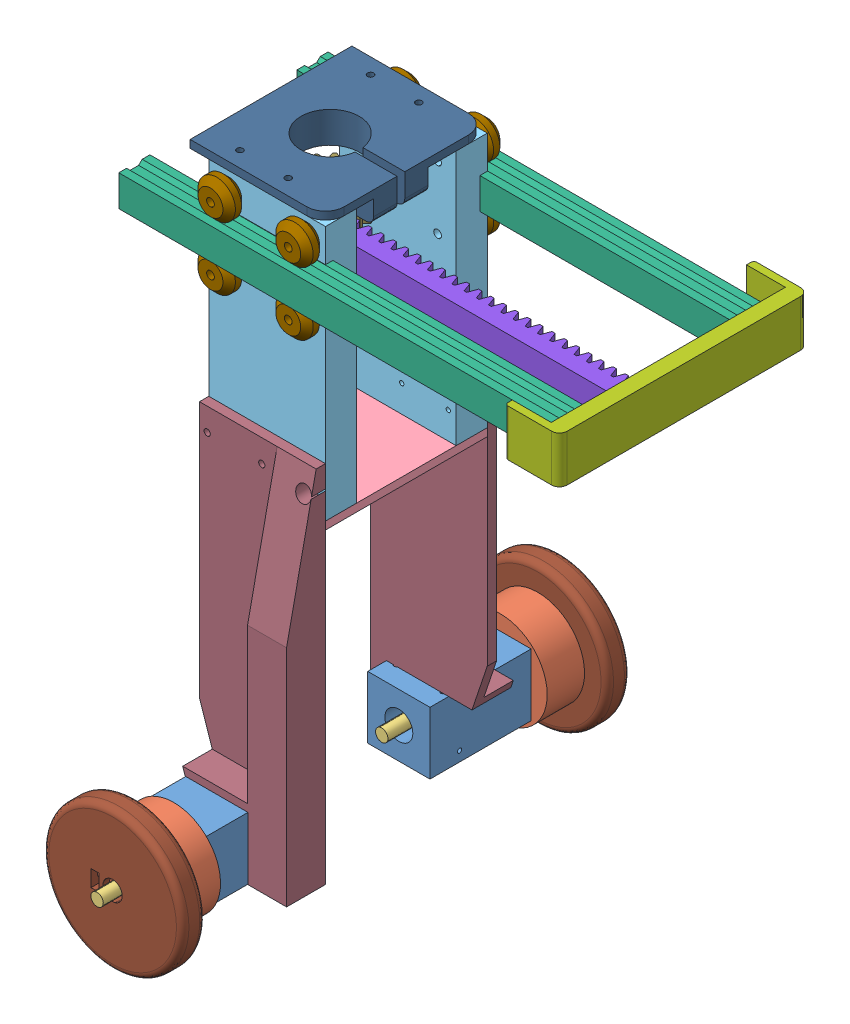
SolidWorks assembly assembly, configuration Default. Lengths in mm.
Overall size (288 396.18 308).
28 component instances, 14 part files, 40 mates.
Components (placement in the parent):
- backSlider.stp-1-solid27-1: backSlider.stp-1-solid27 [Default] at (-286.5622 -346.0796 -57.1007) x (-1 0 0) z (0 0 1) size (40 40 65)
- Part87-1: Part87 [Default] at (-286.5622 -346.0796 7.8993) x (-0.760275 0.649602 0) z (0 0 1) size (60 60 24)
- Part89-1: Part89 [Default] at (-286.5622 -346.0796 -68.1007) x (-0.760275 0.649602 0) z (0 0 1) size (12.4 12.4 125)
- Part90-1: Part90 [Default] at (-279.2282 -164 -97.1007) x (1 0 0) z (0 -1 0) size (75 104 5)
- Part91-1: Part91 [Default] at (-279.2282 -82 -65.1007) size (75 164 20)
- Part93-1: Part93 [Default] at (-359.3481 -31.25 -39.8507) x (0 -1 0) z (1 0 0) size (20 20 278)
- Part94-1: Part94 [Default] at (-88.8481 -21.25 -105.1005) x (-1 0 0) z (0 -1 0) size (35 160 30)
- Part95-1: Part95 [Default] at (-201.3481 -36.25 -72.9132) x (-1 0 0) z (0 -1 0) size (240 15.62 54)
- Part96-1: Part96 [Default] at (-303.6445 -11.5 -45.1007) x (0.999988 -0.004867 0) z (0 0 1) size (24 24 12)
- Part97-1: Part97 [Default] at (-285.2282 5 -97.1007) x (1 0 0) z (0 -1 0) size (87 104 20)
- wheel front without gear-2: wheel front without gear [Default] at (-813.0302 196.9967 26.563)
- wheel with grat-1: wheel with grat [Default] at (-286.5622 -346.0796 39.3993) x (-0.999998 -0.002215 0) z (0 0 1) size (90 90 15)
- Part96-2: Part96 [Default] at (-253.6445 -11.5 -33.1007) x (-0.928778 -0.370636 0) z (0 0 -1) size (24 24 12)
- Part96-3: Part96 [Default] at (-253.6445 -52 -45.1007) x (0.988499 0.151229 0) z (0 0 1) size (24 24 12)
- Part96-4: Part96 [Default] at (-303.6445 -52 -45.1007) x (0.982944 0.183903 0) z (0 0 1) size (24 24 12)
- Part98-1: Part98 [Default] at (-287.2282 -40.0491 -93.6007) x (1 0 0) z (0 1 0) size (40 39.32 20)
- Part99-1: Part99 [Default] at (-279.2282 -249.1667 -45.1007) x (-1 0 0) z (0 0 1) size (75 234.33 25)
- Part91-3: Part91 [Default] at (-279.2282 -82 -149.1007) size (75 164 20)
- Part96-9: Part96 [Default] at (-253.6445 -11.5 -149.1007) x (-0.928778 -0.370636 0) z (0 0 -1) size (24 24 12)
- Part96-10: Part96 [Default] at (-303.6445 -11.5 -161.1007) x (0.999988 -0.004867 0) z (0 0 1) size (24 24 12)
- Part96-11: Part96 [Default] at (-303.6445 -52 -161.1007) x (0.982944 0.183903 0) z (0 0 1) size (24 24 12)
- Part93-3: Part93 [Default] at (-81.3481 -31.25 -154.3507) x (0 -1 0) z (-1 0 0) size (20 20 278)
- Part99-4: Part99 [Default] at (-279.2282 -249.1667 -149.1007) x (1 0 0) z (0 0 -1) size (75 234.33 25)
- backSlider.stp-1-solid27-4: backSlider.stp-1-solid27 [Default] at (-286.5622 -346.0796 -137.1007) x (-1 0 0) z (0 0 -1) size (40 40 65)
- Part87-4: Part87 [Default] at (-286.5622 -346.0796 -226.1007) x (-0.760275 0.649602 0) z (0 0 1) size (60 60 24)
- wheel with grat-4: wheel with grat [Default] at (-286.5622 -346.0796 -233.6007) x (-0.999998 -0.002215 0) z (0 0 -1) size (90 90 15)
- Part89-4: Part89 [Default] at (-286.5622 -346.0796 -251.1007) x (-0.760275 0.649602 0) z (0 0 1) size (12.4 12.4 125)
- Part96-12: Part96 [Default] at (-253.6445 -52 -161.1007) x (0.988499 0.151229 0) z (0 0 1) size (24 24 12)
Mates (geometry in assembly coordinates):
- Coincident1: coincident anti-aligned: plane of Part97-1 through (-285.2282 0 -97.1007) normal (0 -1 0)
- Coincident2: coincident aligned: plane of Part91-1 through (-279.2282 -82 -45.1007) normal (0 0 1); plane of Part97-1 through (-285.2282 0 -45.1007) normal (0 0 1)
- Coincident3: coincident anti-aligned: plane of Part91-1 through (-241.7282 0 -45.1007) normal (0 1 0); plane of Part97-1 through (-285.2282 0 -97.1007) normal (0 -1 0)
- Coincident4: coincident aligned: plane of Part91-1 through (-241.7282 -164 -45.1007) normal (1 0 0); plane of Part97-1 through (-241.7282 0 -97.1007) normal (1 0 0)
- Concentric1: concentric aligned: cylinder of Part91-1 through (-303.6445 -11.5 -45.1007) axis (0 0 -1) radius 2.5; cylinder of Part96-1 through (-303.6445 -11.5 -33.1007) axis (0 0 -1) radius 2.5
- Coincident5: coincident anti-aligned: plane of Part91-1 through (-279.2282 -82 -45.1007) normal (0 0 1); plane of Part96-1 through (-303.6445 -11.5 -45.1007) normal (0 0 -1)
- Concentric2: concentric aligned: cylinder of Part91-1 through (-253.6445 -11.5 -45.1007) axis (0 0 -1) radius 2.5; circle of Part96-2
- Concentric3: concentric aligned: cylinder of Part91-1 through (-253.6445 -52 -45.1007) axis (0 0 -1) radius 2.5; cylinder of Part96-3 through (-253.6445 -52 -33.1007) axis (0 0 -1) radius 2.5
- Concentric4: concentric aligned: cylinder of Part91-1 through (-303.6445 -52 -45.1007) axis (0 0 -1) radius 2.5; cylinder of Part96-4 through (-303.6445 -52 -33.1007) axis (0 0 -1) radius 2.5
- Coincident7: coincident anti-aligned: plane of Part91-1 through (-279.2282 -82 -45.1007) normal (0 0 1); plane of Part96-2 through (-253.6445 -11.5 -45.1007) normal (0 0 -1)
- Coincident8: coincident anti-aligned: plane of Part91-1 through (-279.2282 -82 -45.1007) normal (0 0 1); plane of Part96-4 through (-303.6445 -52 -45.1007) normal (0 0 -1)
- Coincident9: coincident anti-aligned: plane of Part91-1 through (-279.2282 -82 -45.1007) normal (0 0 1); plane of Part96-3 through (-253.6445 -52 -45.1007) normal (0 0 -1)
- Concentric5: concentric anti-aligned: cylinder of Part97-1 through (-287.2282 -15 -93.6007) axis (0 1 0) radius 18.75; cylinder of Part98-1 through (-287.2282 -20.0491 -93.6007) axis (0 -1 0) radius 1.2268
- Parallel2: parallel anti-aligned: plane of Part93-1 through (-81.3481 -39 -37.1007) normal (0 -1 0); plane of Part97-1 through (-285.2282 5 -97.1007) normal (0 1 0)
- Parallel3: parallel aligned: plane of Part91-1 through (-241.7282 -164 -45.1007) normal (1 0 0); plane of Part93-1 through (-81.3481 -31.25 -39.8507) normal (1 0 0)
- Tangent1: tangent anti-aligned: plane of Part93-1 through (-81.3481 -23.5 -42.6007) normal (0 1 0); cylinder of Part96-2 through (-253.6445 -11.5 -45.1007) axis (0 0 1) radius 12
- Tangent2: tangent anti-aligned: plane of Part93-1 through (-81.3481 -23.5 -37.1007) normal (0 0.707108 -0.707106); cone of Part96-2 through (-253.6445 -11.5 -37.1007) axis (0 0 1)
- Coincident12: coincident anti-aligned: plane of Part93-1 through (-81.3481 -21.25 -29.8507) normal (0 0 1); plane of Part94-1 through (-106.3481 -51.25 -29.8507) normal (0 0 -1)
- Coincident13: coincident anti-aligned: plane of Part93-1 through (-81.3481 -31.25 -39.8507) normal (1 0 0); plane of Part94-1 through (-81.3481 -51.25 -29.8507) normal (-1 0 0)
- Coincident14: coincident aligned: plane of Part93-1 through (-81.3481 -21.25 -34.8507) normal (0 1 0); plane of Part94-1 through (-76.3481 -21.25 -180.1004) normal (0 1 0)
- Coincident15: coincident anti-aligned: plane of Part94-1 through (-81.3481 -51.25 -29.8507) normal (-1 0 0); plane of Part95-1 through (-81.3481 -51.25 -72.9132) normal (1 0 0)
- Coincident16: coincident aligned: plane of Part94-1 through (-76.3481 -21.25 -180.1004) normal (0 1 0); plane of Part95-1 through (-201.3481 -21.25 -72.9132) normal (0 1 0)
- Coincident17: coincident aligned: plane of Part94-1 through (-76.3481 -21.25 -180.1004) normal (0 1 0); plane of Part95-1 through (-201.3481 -21.25 -72.9132) normal (0 1 0)
- Coincident19: coincident anti-aligned: plane of Part91-1 through (-279.2282 -82 -45.1007) normal (0 0 1); plane of Part99-1 through (-279.2282 -249.1667 -45.1007) normal (0 0 -1)
- Coincident21: coincident aligned: plane of Part91-1 through (-241.7282 -164 -45.1007) normal (1 0 0); plane of Part99-1 through (-241.7282 -249.1667 -39.1007) normal (1 0 0)
- Concentric8: concentric aligned: cylinder of Part91-1 through (-311.7606 -146.6627 -45.1007) axis (0 0 -1) radius 1.4; cylinder of Part99-1 through (-311.7606 -146.6627 -39.1007) axis (0 0 -1) radius 2
- Concentric9: concentric aligned: cylinder of backSlider.stp-1-solid27-1 through (-286.5622 -346.0796 7.8993) axis (0 0 -1) radius 9; cylinder of Part89-1 through (-286.5622 -346.0796 56.8993) axis (0 0 -1) radius 4
- Concentric10: concentric anti-aligned: cylinder of Part89-1 through (-286.5622 -346.0796 56.8993) axis (0 0 -1) radius 4; circle of wheel with grat-1
- Concentric11: concentric aligned: cylinder of backSlider.stp-1-solid27-1 through (-286.5622 -346.0796 7.8993) axis (0 0 -1) radius 9; cylinder of Part87-1 through (-286.5622 -346.0796 31.8993) axis (0 0 -1) radius 12.5
- Coincident22: coincident anti-aligned: plane of Part87-1 through (-286.1973 -346.3915 31.8993) normal (0 0 1); plane of wheel with grat-1 through (-286.5622 -346.0796 31.8993) normal (0 0 -1)
- Coincident23: coincident anti-aligned: plane of backSlider.stp-1-solid27-1 through (-286.5622 -346.0796 7.8993) normal (0 0 1); plane of Part87-1 through (-286.1973 -346.3915 7.8993) normal (0 0 -1)
- Distance1: distance = 10 mm aligned: plane of wheel with grat-1 through (-286.5622 -346.0796 46.8993) normal (0 0 1); plane of Part89-1 through (-286.5622 -346.0796 56.8993) normal (0 0 1)
- Coincident27: coincident anti-aligned: plane of backSlider.stp-1-solid27-1 through (-266.5622 -326.0796 7.8993) normal (1 0 0); plane of Part99-1 through (-266.5622 -249.1667 -39.1007) normal (-1 0 0)
- Coincident28: coincident anti-aligned: plane of backSlider.stp-1-solid27-1 through (-266.5622 -326.0796 7.8993) normal (0 1 0); plane of Part99-1 through (-279.2282 -326.0796 -39.1007) normal (0 -1 0)
- Distance2: distance = 67 mm aligned: plane of Part99-1 through (-279.2282 -249.1667 -20.1007) normal (0 0 1); plane of wheel with grat-1 through (-286.5622 -346.0796 46.8993) normal (0 0 1)
- Coincident29: coincident anti-aligned: plane of Part90-1 through (-279.2282 -164 -97.1007) normal (0 1 0); plane of Part91-1 through (-316.7282 -164 -45.1007) normal (0 -1 0)
- Parallel5: parallel aligned: plane of Part90-1 through (-241.7282 -169 -149.1007) normal (1 0 0); plane of Part99-1 through (-241.7282 -249.1667 -39.1007) normal (1 0 0)
- Coincident30: coincident anti-aligned: plane of Part90-1 through (-241.7282 -169 -45.1007) normal (0 0 1); plane of Part99-1 through (-279.2282 -249.1667 -45.1007) normal (0 0 -1)
- Coincident31: coincident aligned: plane of Part90-1 through (-241.7282 -169 -149.1007) normal (1 0 0); plane of Part99-1 through (-241.7282 -249.1667 -39.1007) normal (1 0 0)
- Coincident32: coincident anti-aligned: plane of Part91-1 through (-279.2282 -82 -65.1007) normal (0 0 -1); plane of Part95-1 through (-201.3481 -51.25 -65.1007) normal (0 0 1)
